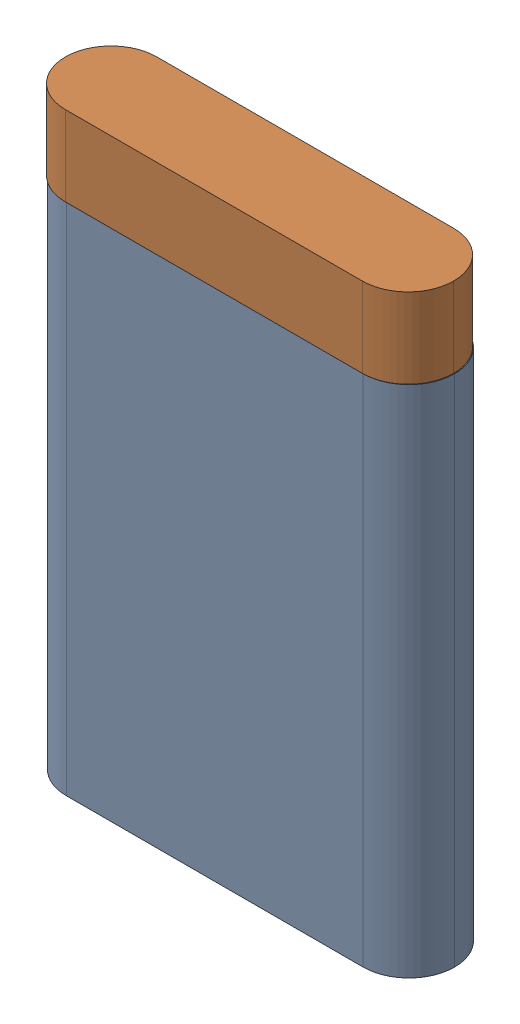
SolidWorks assembly LiIon, configuration Default. Lengths in mm.
Overall size (34.07 52 8).
2 component instances, 2 part files, 1 mates.
Components (placement in the parent):
- Li_Ion_Part1-1: Li_Ion_Part1 [Default] at (-19.7691 -13.4911 19.5116) size (34 45 8)
- Li_Ion_Part2-1: Li_Ion_Part2 [Default] at (-9.9309 31.5089 27.5162) size (34 7 8)
Mates (geometry in assembly coordinates):
- Coincident2: coincident anti-aligned: plane of Li_Ion_Part1-1 through (-19.7691 31.5089 27.5116) normal (0 1 0); plane of Li_Ion_Part2-1 through (-9.9309 31.5089 27.5162) normal (0 -1 0)
